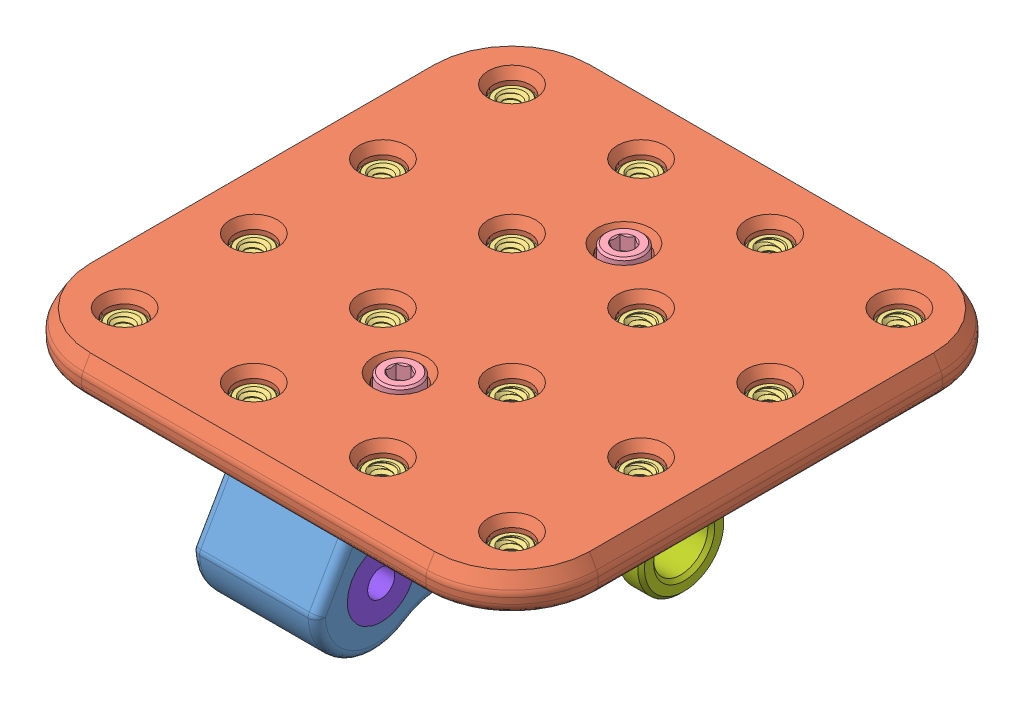
SolidWorks assembly LCSA-2, configuration LCSA-2. Lengths in mm.
Overall size (76.2 32.01 76.2).
33 component instances, 8 part files, 94 mates.
Components (placement in the parent):
- LCSAP-202-1: LCSAP-202 [LCSAP-202] at (-4.5942 14.1847 0) size (19.49 26.67 76.19)
- LCSAP-201-1: LCSAP-201 [LCSAP-201] at (-4.5942 25.2972 0) x (0 0 1) z (-1 0 0) size (76.2 5.08 76.2)
- 95117A433-1: 95117A433 [95117A433] at (23.9808 25.2972 28.575) x (0 0 1) z (0 -1 0) size (7.11 7.11 3.83)
- 95117A433-2: 95117A433 [95117A433] at (4.9308 25.2972 28.575) x (0 0 1) z (0 -1 0) size (7.11 7.11 3.83)
- 95117A433-3: 95117A433 [95117A433] at (23.9808 25.2972 9.525) x (0 0 1) z (0 -1 0) size (7.11 7.11 3.83)
- 95117A433-4: 95117A433 [95117A433] at (23.9808 25.2972 -9.525) x (0 0 1) z (0 -1 0) size (7.11 7.11 3.83)
- 95117A433-5: 95117A433 [95117A433] at (4.9308 25.2972 9.525) x (0 0 1) z (0 -1 0) size (7.11 7.11 3.83)
- 95117A433-6: 95117A433 [95117A433] at (4.9308 25.2972 -9.525) x (0 0 1) z (0 -1 0) size (7.11 7.11 3.83)
- 95117A433-7: 95117A433 [95117A433] at (23.9808 25.2972 -28.575) x (0 0 1) z (0 -1 0) size (7.11 7.11 3.83)
- 95117A433-8: 95117A433 [95117A433] at (4.9308 25.2972 -28.575) x (0 0 1) z (0 -1 0) size (7.11 7.11 3.83)
- 95117A433-11: 95117A433 [95117A433] at (-14.1192 25.2972 28.575) x (0 0 -1) z (0 -1 0) size (7.11 7.11 3.83)
- 95117A433-12: 95117A433 [95117A433] at (-33.1692 25.2972 28.575) x (0 0 -1) z (0 -1 0) size (7.11 7.11 3.83)
- 95117A433-13: 95117A433 [95117A433] at (-14.1192 25.2972 9.525) x (0 0 -1) z (0 -1 0) size (7.11 7.11 3.83)
- 95117A433-14: 95117A433 [95117A433] at (-14.1192 25.2972 -9.525) x (0 0 -1) z (0 -1 0) size (7.11 7.11 3.83)
- 95117A433-15: 95117A433 [95117A433] at (-14.1192 25.2972 -28.575) x (0 0 -1) z (0 -1 0) size (7.11 7.11 3.83)
- 95117A433-16: 95117A433 [95117A433] at (-33.1692 25.2972 -28.575) x (0 0 -1) z (0 -1 0) size (7.11 7.11 3.83)
- 95117A433-17: 95117A433 [95117A433] at (-33.1692 25.2972 -9.525) x (0 0 -1) z (0 -1 0) size (7.11 7.11 3.83)
- 95117A433-18: 95117A433 [95117A433] at (-33.1692 25.2972 9.525) x (0 0 -1) z (0 -1 0) size (7.11 7.11 3.83)
- 92196A150-1: 92196A150 [92196A150] at (-16.6592 12.7242 7.9375) x (0 0.5 0.866025) z (-1 0 0) size (5.74 5.74 19.85)
- 92196A150-2: 92196A150 [92196A150] at (-16.6592 12.7242 -7.9375) x (0 1 0) z (-1 0 0) size (5.74 5.74 19.85)
- 92196A150-3: 92196A150 [92196A150] at (-4.5942 11.1001 16.51) x (1 0 0) z (0 -1 0) size (5.74 5.74 19.85)
- 92196A150-4: 92196A150 [92196A150] at (-4.5942 11.1001 -16.51) x (1 0 0) z (0 -1 0) size (5.74 5.74 19.85)
- 92196A150-5: 92196A150 [92196A150] at (-16.6592 20.6617 0) x (0 0.5 0.866025) z (-1 0 0) size (5.74 5.74 19.85)
- 92196A150-7: 92196A150 [92196A150] at (-16.6592 4.7867 0) x (0 0.5 0.866025) z (-1 0 0) size (5.74 5.74 19.85)
- 94855A201-1: 94855A201 [94855A201] at (-4.5942 10.5573 16.51) x (0 0 -1) z (-1 0 0) size (7.94 3.39 7.94)
- 94855A201-2: 94855A201 [94855A201] at (-4.5942 10.5573 -16.51) x (0 0 1) z (1 0 0) size (7.94 3.39 7.94)
- 90480A007-1: 90480A007 [90480A007] at (-12.3333 12.7242 7.9375) x (0 0.866025 0.5) z (0 -0.5 0.866025) size (7.94 3.39 9.17)
- 90480A007-2: 90480A007 [90480A007] at (-12.3333 12.7242 -7.9375) x (0 0.866025 -0.5) z (0 0.5 0.866025) size (7.94 3.39 9.17)
- 90480A007-3: 90480A007 [90480A007] at (-12.3333 20.6617 0) x (0 -0.5 0.866025) z (0 -0.866025 -0.5) size (7.94 3.39 9.17)
- 90480A007-5: 90480A007 [90480A007] at (-12.3333 4.7867 0) x (0 -0.5 0.866025) z (0 -0.866025 -0.5) size (7.94 3.39 9.17)
- T8-AB-1: T8-AB [T8-AB] at (-4.5942 12.7242 0) x (0 -1 0) z (0 0 1) size (22.23 25.4 22.23)
- 6659K650-1: 6659K650 [6659K65] at (4.6813 14.1847 -28.575) x (0 1 0) z (0 0 1) size (10 6 10)
- 6659K650-2: 6659K650 [6659K65] at (4.6813 14.1847 28.575) x (0 0.987351 0.158553) z (0 -0.158553 0.987351) size (10 6 10)
Mates (geometry in assembly coordinates):
- Coincident31: coincident anti-aligned: plane of LCSAP-202-1 through (-4.5942 11.9463 0) normal (0 -1 0); plane of 94855A201-1 through (-8.5629 11.9463 20.4788) normal (0 1 0)
- Concentric13: concentric anti-aligned: circle of LCSAP-202-1; circle of 94855A201-1
- Coincident32: coincident anti-aligned: plane of LCSAP-202-1 through (-8.5629 11.9463 20.4788) normal (1 0 0); plane of 94855A201-1 through (-8.5629 9.1682 20.4788) normal (-1 0 0)
- Coincident33: coincident anti-aligned: plane of LCSAP-202-1 through (-4.5942 11.9463 0) normal (0 -1 0); plane of 94855A201-2 through (-0.6254 11.9463 -20.4788) normal (0 1 0)
- Concentric14: concentric aligned: circle of LCSAP-202-1; circle of 94855A201-2
- Coincident34: coincident anti-aligned: plane of LCSAP-202-1 through (-0.6254 11.9463 -12.5412) normal (-1 0 0); plane of 94855A201-2 through (-0.6254 9.1682 -20.4788) normal (1 0 0)
- Concentric15: concentric anti-aligned: cylinder of LCSAP-201-1 through (-4.5942 26.4402 16.51) axis (0 1 0) radius 3.175; cylinder of 92196A150-3 through (-4.5942 30.4803 16.51) axis (0 -1 0) radius 2.8702
- Coincident35: coincident aligned: cone of LCSAP-201-1 through (-4.5942 26.4402 16.51) axis (0 -1 0); circle of 92196A150-3
- Parallel9: parallel aligned: plane of LCSAP-201-1 through (33.5058 30.3772 -38.1) normal (1 0 0); plane of 92196A150-3 through (-5.9833 28.3967 15.708) normal (1 0 0)
- Concentric16: concentric anti-aligned: cylinder of LCSAP-201-1 through (-4.5942 26.4402 -16.51) axis (0 1 0) radius 3.175; cylinder of 92196A150-4 through (-4.5942 30.4803 -16.51) axis (0 -1 0) radius 2.8702
- Parallel10: parallel aligned: plane of LCSAP-201-1 through (33.5058 30.3772 -38.1) normal (1 0 0); plane of 92196A150-4 through (-5.9833 28.3967 -17.312) normal (1 0 0)
- Coincident38: coincident anti-aligned: plane of LCSAP-201-1 through (23.9808 27.0752 28.575) normal (0 -1 0); plane of 95117A433-1 through (23.9808 27.0752 28.575) normal (0 1 0)
- Concentric17: concentric aligned: cylinder of LCSAP-201-1 through (23.9808 27.0752 28.575) axis (0 -1 0) radius 3.81; cylinder of 95117A433-1 through (23.9808 27.0752 28.575) axis (0 -1 0) radius 3.556
- Parallel11: parallel anti-aligned: plane of LCSAP-201-1 through (33.5058 30.3772 -38.1) normal (1 0 0); plane of 95117A433-1 through (23.9808 25.2972 28.575) normal (-1 0 0)
- Coincident40: coincident anti-aligned: plane of LCSAP-201-1 through (4.9308 27.0752 28.575) normal (0 -1 0); plane of 95117A433-2 through (4.9308 27.0752 28.575) normal (0 1 0)
- Concentric18: concentric aligned: cylinder of LCSAP-201-1 through (4.9308 27.0752 28.575) axis (0 -1 0) radius 3.81; cylinder of 95117A433-2 through (4.9308 27.0752 28.575) axis (0 -1 0) radius 3.556
- Parallel12: parallel anti-aligned: plane of LCSAP-201-1 through (33.5058 30.3772 -38.1) normal (1 0 0); plane of 95117A433-2 through (4.9308 25.2972 28.575) normal (-1 0 0)
- Coincident41: coincident anti-aligned: plane of LCSAP-201-1 through (23.9808 27.0752 9.525) normal (0 -1 0); plane of 95117A433-3 through (23.9808 27.0752 9.525) normal (0 1 0)
- Concentric19: concentric aligned: cylinder of LCSAP-201-1 through (23.9808 27.0752 9.525) axis (0 -1 0) radius 3.81; cylinder of 95117A433-3 through (23.9808 27.0752 9.525) axis (0 -1 0) radius 3.556
- Parallel13: parallel anti-aligned: plane of LCSAP-201-1 through (33.5058 30.3772 -38.1) normal (1 0 0); plane of 95117A433-3 through (23.9808 25.2972 9.525) normal (-1 0 0)
- Coincident42: coincident anti-aligned: plane of LCSAP-201-1 through (23.9808 27.0752 -9.525) normal (0 -1 0); plane of 95117A433-4 through (23.9808 27.0752 -9.525) normal (0 1 0)
- Concentric20: concentric aligned: cylinder of LCSAP-201-1 through (23.9808 27.0752 -9.525) axis (0 -1 0) radius 3.81; cylinder of 95117A433-4 through (23.9808 27.0752 -9.525) axis (0 -1 0) radius 3.556
- Parallel14: parallel anti-aligned: plane of LCSAP-201-1 through (33.5058 30.3772 -38.1) normal (1 0 0); plane of 95117A433-4 through (23.9808 25.2972 -9.525) normal (-1 0 0)
- Coincident43: coincident anti-aligned: plane of LCSAP-201-1 through (4.9308 27.0752 9.525) normal (0 -1 0); plane of 95117A433-5 through (4.9308 27.0752 9.525) normal (0 1 0)
- Concentric21: concentric aligned: cylinder of LCSAP-201-1 through (4.9308 27.0752 9.525) axis (0 -1 0) radius 3.81; cylinder of 95117A433-5 through (4.9308 27.0752 9.525) axis (0 -1 0) radius 3.556
- Parallel15: parallel anti-aligned: plane of LCSAP-201-1 through (33.5058 30.3772 -38.1) normal (1 0 0); plane of 95117A433-5 through (4.9308 25.2972 9.525) normal (-1 0 0)
- Coincident44: coincident anti-aligned: plane of LCSAP-201-1 through (4.9308 27.0752 -9.525) normal (0 -1 0); plane of 95117A433-6 through (4.9308 27.0752 -9.525) normal (0 1 0)
- Concentric22: concentric aligned: cylinder of LCSAP-201-1 through (4.9308 27.0752 -9.525) axis (0 -1 0) radius 3.81; cylinder of 95117A433-6 through (4.9308 27.0752 -9.525) axis (0 -1 0) radius 3.556
- Parallel16: parallel anti-aligned: plane of LCSAP-201-1 through (33.5058 30.3772 -38.1) normal (1 0 0); plane of 95117A433-6 through (4.9308 25.2972 -9.525) normal (-1 0 0)
- Coincident45: coincident anti-aligned: plane of LCSAP-201-1 through (23.9808 27.0752 -28.575) normal (0 -1 0); plane of 95117A433-7 through (23.9808 27.0752 -28.575) normal (0 1 0)
- Concentric23: concentric aligned: cylinder of LCSAP-201-1 through (23.9808 27.0752 -28.575) axis (0 -1 0) radius 3.81; cylinder of 95117A433-7 through (23.9808 27.0752 -28.575) axis (0 -1 0) radius 3.556
- Parallel17: parallel anti-aligned: plane of LCSAP-201-1 through (33.5058 30.3772 -38.1) normal (1 0 0); plane of 95117A433-7 through (23.9808 25.2972 -28.575) normal (-1 0 0)
- Coincident46: coincident anti-aligned: plane of LCSAP-201-1 through (4.9308 27.0752 -28.575) normal (0 -1 0); plane of 95117A433-8 through (4.9308 27.0752 -28.575) normal (0 1 0)
- Concentric24: concentric aligned: cylinder of LCSAP-201-1 through (4.9308 27.0752 -28.575) axis (0 -1 0) radius 3.81; cylinder of 95117A433-8 through (4.9308 27.0752 -28.575) axis (0 -1 0) radius 3.556
- Parallel18: parallel anti-aligned: plane of LCSAP-201-1 through (33.5058 30.3772 -38.1) normal (1 0 0); plane of 95117A433-8 through (4.9308 25.2972 -28.575) normal (-1 0 0)
- Coincident48: coincident anti-aligned: plane of LCSAP-201-1 through (-14.1192 27.0752 28.575) normal (0 -1 0); plane of 95117A433-11 through (-14.1192 27.0752 28.575) normal (0 1 0)
- Concentric25: concentric aligned: cylinder of LCSAP-201-1 through (-14.1192 27.0752 28.575) axis (0 -1 0) radius 3.81; cylinder of 95117A433-11 through (-14.1192 27.0752 28.575) axis (0 -1 0) radius 3.556
- Parallel19: parallel anti-aligned: plane of LCSAP-201-1 through (-42.6942 30.3772 -38.1) normal (-1 0 0); plane of 95117A433-11 through (-14.1192 25.2972 28.575) normal (1 0 0)
- Coincident49: coincident anti-aligned: plane of LCSAP-201-1 through (-33.1692 27.0752 28.575) normal (0 -1 0); plane of 95117A433-12 through (-33.1692 27.0752 28.575) normal (0 1 0)
- Concentric26: concentric aligned: cylinder of LCSAP-201-1 through (-33.1692 27.0752 28.575) axis (0 -1 0) radius 3.81; cylinder of 95117A433-12 through (-33.1692 27.0752 28.575) axis (0 -1 0) radius 3.556
- Parallel20: parallel anti-aligned: plane of LCSAP-201-1 through (-42.6942 30.3772 -38.1) normal (-1 0 0); plane of 95117A433-12 through (-33.1692 25.2972 28.575) normal (1 0 0)
- Coincident50: coincident anti-aligned: plane of LCSAP-201-1 through (-14.1192 27.0752 9.525) normal (0 -1 0); plane of 95117A433-13 through (-14.1192 27.0752 9.525) normal (0 1 0)
- Concentric27: concentric aligned: cylinder of LCSAP-201-1 through (-14.1192 27.0752 9.525) axis (0 -1 0) radius 3.81; cylinder of 95117A433-13 through (-14.1192 27.0752 9.525) axis (0 -1 0) radius 3.556
- Parallel21: parallel anti-aligned: plane of LCSAP-201-1 through (-42.6942 30.3772 -38.1) normal (-1 0 0); plane of 95117A433-13 through (-14.1192 25.2972 9.525) normal (1 0 0)
- Coincident51: coincident anti-aligned: plane of LCSAP-201-1 through (-14.1192 27.0752 -9.525) normal (0 -1 0); plane of 95117A433-14 through (-14.1192 27.0752 -9.525) normal (0 1 0)
- Concentric28: concentric aligned: cylinder of LCSAP-201-1 through (-14.1192 27.0752 -9.525) axis (0 -1 0) radius 3.81; cylinder of 95117A433-14 through (-14.1192 27.0752 -9.525) axis (0 -1 0) radius 3.556
- Parallel22: parallel anti-aligned: plane of LCSAP-201-1 through (-42.6942 30.3772 -38.1) normal (-1 0 0); plane of 95117A433-14 through (-14.1192 25.2972 -9.525) normal (1 0 0)
- Coincident52: coincident anti-aligned: plane of LCSAP-201-1 through (-14.1192 27.0752 -28.575) normal (0 -1 0); plane of 95117A433-15 through (-14.1192 27.0752 -28.575) normal (0 1 0)
- Concentric29: concentric aligned: cylinder of LCSAP-201-1 through (-14.1192 27.0752 -28.575) axis (0 -1 0) radius 3.81; cylinder of 95117A433-15 through (-14.1192 27.0752 -28.575) axis (0 -1 0) radius 3.556
- Parallel23: parallel anti-aligned: plane of LCSAP-201-1 through (-42.6942 30.3772 -38.1) normal (-1 0 0); plane of 95117A433-15 through (-14.1192 25.2972 -28.575) normal (1 0 0)
- Coincident53: coincident anti-aligned: plane of LCSAP-201-1 through (-33.1692 27.0752 -28.575) normal (0 -1 0); plane of 95117A433-16 through (-33.1692 27.0752 -28.575) normal (0 1 0)
- Concentric30: concentric aligned: cylinder of LCSAP-201-1 through (-33.1692 27.0752 -28.575) axis (0 -1 0) radius 3.81; cylinder of 95117A433-16 through (-33.1692 27.0752 -28.575) axis (0 -1 0) radius 3.556
- Parallel24: parallel anti-aligned: plane of LCSAP-201-1 through (-42.6942 30.3772 -38.1) normal (-1 0 0); plane of 95117A433-16 through (-33.1692 25.2972 -28.575) normal (1 0 0)
- Coincident54: coincident anti-aligned: plane of LCSAP-201-1 through (-33.1692 27.0752 -9.525) normal (0 -1 0); plane of 95117A433-17 through (-33.1692 27.0752 -9.525) normal (0 1 0)
- Concentric31: concentric aligned: cylinder of LCSAP-201-1 through (-33.1692 27.0752 -9.525) axis (0 -1 0) radius 3.81; cylinder of 95117A433-17 through (-33.1692 27.0752 -9.525) axis (0 -1 0) radius 3.556
- Parallel25: parallel anti-aligned: plane of LCSAP-201-1 through (-42.6942 30.3772 -38.1) normal (-1 0 0); plane of 95117A433-17 through (-33.1692 25.2972 -9.525) normal (1 0 0)
- Coincident55: coincident anti-aligned: plane of LCSAP-201-1 through (-33.1692 27.0752 9.525) normal (0 -1 0); plane of 95117A433-18 through (-33.1692 27.0752 9.525) normal (0 1 0)
- Concentric32: concentric aligned: cylinder of LCSAP-201-1 through (-33.1692 27.0752 9.525) axis (0 -1 0) radius 3.81; cylinder of 95117A433-18 through (-33.1692 27.0752 9.525) axis (0 -1 0) radius 3.556
- Parallel26: parallel anti-aligned: plane of LCSAP-201-1 through (-42.6942 30.3772 -38.1) normal (-1 0 0); plane of 95117A433-18 through (-33.1692 25.2972 9.525) normal (1 0 0)
- Coincident56: coincident: cone of LCSAP-201-1 through (-4.5942 26.4402 -16.51) axis (0 -1 0); circle of 92196A150-4
- Coincident59: coincident anti-aligned: plane of LCSAP-202-1 through (-4.5942 12.7242 0) normal (1 0 0); plane of T8-AB-1 through (-4.5942 16.7242 0) normal (-1 0 0)
- Concentric35: concentric aligned: circle of LCSAP-202-1; cylinder of T8-AB-1 through (-0.7842 12.7242 -7.9375) axis (-1 0 0) radius 1.5875
- Coincident60: coincident anti-aligned: plane of 92196A150-1 through (-0.7842 12.7242 7.9375) normal (-1 0 0); plane of T8-AB-1 through (-0.7842 23.8367 0) normal (1 0 0)
- Concentric37: concentric anti-aligned: cylinder of LCSAP-202-1 through (-14.3408 12.7242 7.9375) axis (1 0 0) radius 1.905; cylinder of 92196A150-1 through (2.721 12.7242 7.9375) axis (-1 0 0) radius 2.8702
- Parallel27: parallel aligned: plane of LCSAP-201-1 through (-4.5942 25.2972 0) normal (0 -1 0); plane of 92196A150-1 through (0.6374 14.1133 7.1355) normal (0 -1 0)
- Coincident62: coincident anti-aligned: plane of 92196A150-2 through (-0.7842 12.7242 -7.9375) normal (-1 0 0); plane of T8-AB-1 through (-0.7842 23.8367 0) normal (1 0 0)
- Concentric38: concentric aligned: cylinder of 92196A150-2 through (2.721 12.7242 -7.9375) axis (-1 0 0) radius 2.8702; cylinder of T8-AB-1 through (-0.7842 12.7242 -7.9375) axis (-1 0 0) radius 1.5875
- Parallel28: parallel aligned: plane of LCSAP-201-1 through (-4.5942 25.2972 0) normal (0 -1 0); plane of 92196A150-2 through (0.6374 14.1133 -8.7395) normal (0 -1 0)
- Concentric39: concentric anti-aligned: cylinder of 92196A150-2 through (2.721 12.7242 -7.9375) axis (-1 0 0) radius 2.8702; circle of 90480A007-2
- Coincident64: coincident anti-aligned: plane of LCSAP-202-1 through (-10.9442 -3.2778 0) normal (-1 0 0); plane of 90480A007-2 through (-10.9442 8.1415 -7.9375) normal (1 0 0)
- Perpendicular1: perpendicular: plane of LCSAP-201-1 through (-4.5942 25.2972 0) normal (0 -1 0); plane of 90480A007-2 through (-13.7223 10.4328 -3.9688) normal (0 0 1)
- Coincident66: coincident anti-aligned: plane of LCSAP-202-1 through (-10.9442 -3.2778 0) normal (-1 0 0); plane of 90480A007-1 through (-10.9442 10.4328 3.9688) normal (1 0 0)
- Concentric40: concentric anti-aligned: circle of LCSAP-202-1; circle of 90480A007-1
- Parallel30: parallel anti-aligned: plane of 90480A007-1 through (-13.7223 15.0156 3.9688) normal (0 0 -1); plane of 90480A007-2 through (-13.7223 10.4328 -3.9688) normal (0 0 1)
- Coincident73: coincident anti-aligned: plane of LCSAP-202-1 through (-4.5942 25.2972 0) normal (0 1 0); plane of LCSAP-201-1 through (-4.5942 25.2972 0) normal (0 -1 0)
- Concentric42: concentric aligned: circle of 92196A150-3; circle of 94855A201-1
- Concentric43: concentric aligned: circle of 92196A150-4; circle of 94855A201-2
- Coincident74: coincident anti-aligned: plane of T8-AB-1 through (-0.7842 23.8367 0) normal (1 0 0); plane of 92196A150-5 through (-0.7842 20.6617 0) normal (-1 0 0)
- Concentric45: concentric anti-aligned: circle of T8-AB-1; cylinder of 92196A150-5 through (2.721 20.6617 0) axis (-1 0 0) radius 2.8702
- Parallel34: parallel aligned: plane of LCSAP-201-1 through (-4.5942 25.2972 0) normal (0 -1 0); plane of 92196A150-5 through (0.6374 22.0508 -0.802) normal (0 -1 0)
- Coincident75: coincident anti-aligned: plane of T8-AB-1 through (-0.7842 23.8367 0) normal (1 0 0); plane of 92196A150-7 through (-0.7842 4.7867 0) normal (-1 0 0)
- Concentric46: concentric aligned: circle of T8-AB-1; cylinder of 92196A150-7 through (2.721 4.7867 0) axis (-1 0 0) radius 2.8702
- Parallel35: parallel aligned: plane of LCSAP-201-1 through (-4.5942 25.2972 0) normal (0 -1 0); plane of 92196A150-7 through (0.6374 6.1758 -0.802) normal (0 -1 0)
- Coincident76: coincident anti-aligned: plane of LCSAP-202-1 through (-10.9442 -3.2778 0) normal (-1 0 0); plane of 90480A007-3 through (-10.9442 24.6304 -2.2914) normal (1 0 0)
- Concentric47: concentric aligned: circle of 92196A150-5; circle of 90480A007-3
- Parallel36: parallel anti-aligned: plane of LCSAP-201-1 through (-4.5942 25.2972 0) normal (0 -1 0); plane of 90480A007-3 through (-13.7223 24.6304 2.2914) normal (0 1 0)
- Coincident77: coincident anti-aligned: plane of LCSAP-202-1 through (-10.9442 -3.2778 0) normal (-1 0 0); plane of 90480A007-5 through (-10.9442 8.7554 -2.2914) normal (1 0 0)
- Concentric48: concentric aligned: circle of 92196A150-7; circle of 90480A007-5
- Parallel37: parallel anti-aligned: plane of LCSAP-201-1 through (-4.5942 25.2972 0) normal (0 -1 0); plane of 90480A007-5 through (-13.7223 8.7554 2.2914) normal (0 1 0)
- Concentric49: concentric aligned: circle of 92196A150-1; cylinder of T8-AB-1 through (-0.7842 12.7242 7.9375) axis (-1 0 0) radius 1.5875
- Concentric50: concentric anti-aligned: cylinder of LCSAP-202-1 through (-7.6377 14.1847 -28.575) axis (-1 0 0) radius 4; cylinder of 6659K650-1 through (-1.3187 14.1847 -28.575) axis (1 0 0) radius 3.51
- Coincident78: coincident anti-aligned: plane of LCSAP-202-1 through (3.1813 14.1847 -28.575) normal (1 0 0); plane of 6659K650-1 through (3.1813 14.1847 -28.575) normal (-1 0 0)
- Concentric51: concentric anti-aligned: cylinder of LCSAP-202-1 through (-7.6377 14.1847 28.575) axis (-1 0 0) radius 4; cylinder of 6659K650-2 through (-1.3187 14.1847 28.575) axis (1 0 0) radius 3.51
- Coincident79: coincident anti-aligned: plane of LCSAP-202-1 through (3.1813 14.1847 28.575) normal (1 0 0); plane of 6659K650-2 through (3.1813 14.1847 28.575) normal (-1 0 0)
